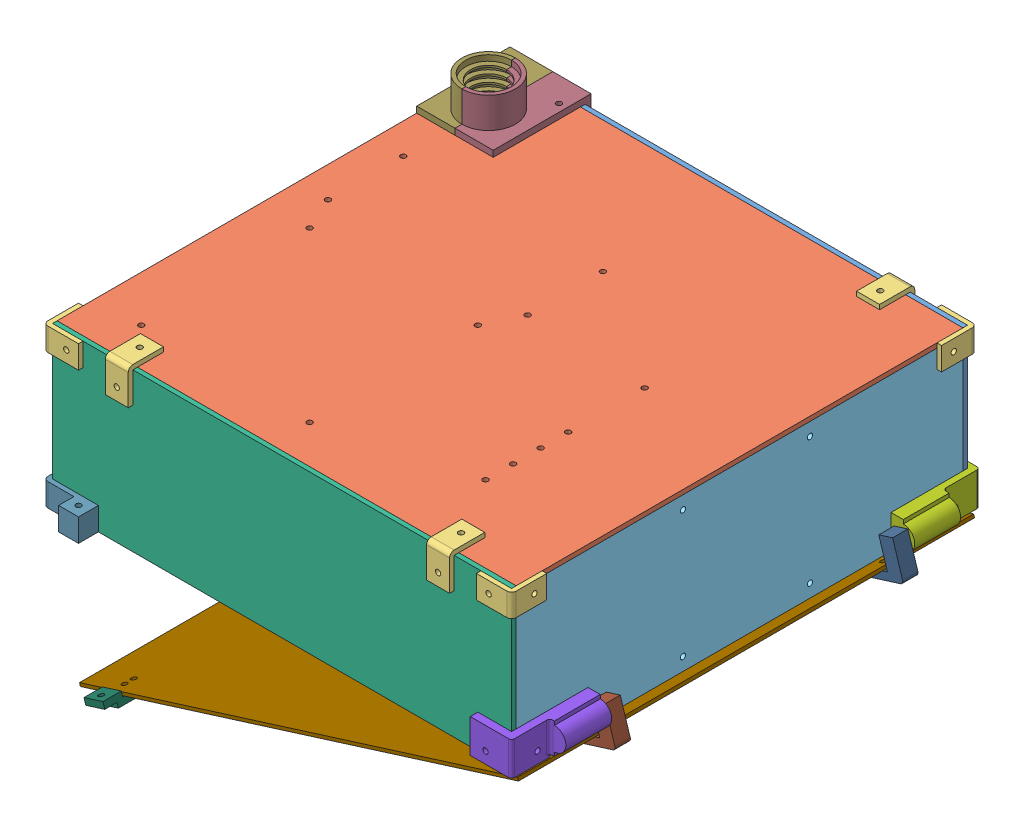
SolidWorks assembly last_assembly, configuration Default. Lengths in mm.
Overall size (321.18 220.37 315).
20 component instances, 15 part files, 55 mates.
Components (placement in the parent):
- baseup-1: baseup [Default] at (-19.8009 112.7119 215.9998) size (300 103 3)
- wall2-1: wall2 [Default] at (-19.8009 212.7119 218.9998) x (1 0 0) z (0 -1 0) size (300 292 3)
- holderr-1: holderr [Default] at (235.1991 204.2119 212.9998) x (0 -1 0) z (0 0 1) size (23 15 23)
- basen-1: basen [Default] at (-16.8009 109.7119 210.9998) x (0 0 1) z (-1 0 0) size (292 100 3)
- left_sidee-1: left_sidee [Default] at (280.1991 109.7119 210.9998) x (0 0 1) z (-1 0 0) size (292 100 3)
- upper_d-1: upper_d [Default] at (-19.8009 112.7119 510.9998) size (300 103 3)
- holderr-3: holderr [Default] at (235.1991 215.7119 505.4998) x (0 0 -1) z (0 -1 0) size (23 15 23)
- holderr-4: holderr [Default] at (25.1991 215.7119 505.4998) x (0 0 -1) z (0 -1 0) size (23 15 23)
- holderr-5: holderr [Default] at (-22.8009 205.2119 505.4998) x (0 0 -1) z (1 0 0) size (23 15 23)
- holderr-6: holderr [Default] at (283.1991 205.2119 505.4998) x (0 0 -1) z (-1 0 0) size (23 15 23)
- holderr-8: holderr [Default] at (271.6991 205.2119 212.9998) x (-1 0 0) z (0 0 1) size (23 15 23)
- hinge1-1: hinge1 [Default] at (280.1991 109.7119 265.9998) x (0 0 -1) z (1 0 0) size (54 22 37.5)
- hinge2-1: hinge2 [Default] at (283.1991 109.7119 516.9998) x (0 1 0) z (-1 0 0) size (22 55 37.5)
- kapi-1: kapi [Default] at (-2.151 18.2479 513.9998) x (0 0 -1) z (0.29874 -0.954334 0) size (298 300 2)
- revoluttt1-1: revoluttt1 [Default] at (290.2842 127.6039 275.9998) x (-0.954334 -0.29874 0) z (0.29874 -0.954334 0) size (29.5 27 23.91)
- upper_revolute-1: upper_revolute [Default] at (283.1267 125.3633 453.9998) x (0.954334 0.29874 0) z (0.29874 -0.954334 0) size (29.5 27 23.91)
- control_cable_up-1: control_cable_up [Default] at (-27.8009 212.7119 220.9998) x (0 0 1) z (0 1 0) size (64 28 46)
- control_cable-2: control_cable [Default] at (38.1991 212.7119 286.9998) x (0 0 -1) z (0 1 0) size (64 25 44)
- totucu-1: totucu [Default] at (-22.8009 117.2119 505.4998) x (0 0 -1) z (1 0 0) size (33 15 33)
- kapi_totucu-1: kapi_totucu [Default] at (13.7739 24.2808 526.9998) x (0 0 -1) z (-0.954334 -0.29874 0) size (30 7 13)
Mates (geometry in assembly coordinates):
- Concentric1: concentric aligned: cylinder of wall2-1 through (235.1991 209.7119 227.9998) axis (0 1 0) radius 1.75; cylinder of holderr-1 through (235.1991 192.7119 227.9998) axis (0 1 0) radius 1.75
- Coincident9: coincident anti-aligned: plane of baseup-1 through (-19.8009 112.7119 218.9998) normal (0 0 1); plane of basen-1 through (-26.8009 209.7119 218.9998) normal (0 0 -1)
- Coincident10: coincident anti-aligned: plane of wall2-1 through (-19.8009 209.7119 218.9998) normal (0 -1 0); plane of basen-1 through (-19.8009 209.7119 210.9998) normal (0 1 0)
- Coincident11: coincident anti-aligned: plane of wall2-1 through (-19.8009 209.7119 218.9998) normal (0 -1 0); plane of basen-1 through (-19.8009 209.7119 210.9998) normal (0 1 0)
- Coincident12: coincident aligned: plane of wall2-1 through (-19.8009 209.7119 218.9998) normal (-1 0 0); plane of basen-1 through (-19.8009 109.7119 210.9998) normal (-1 0 0)
- Coincident13: coincident aligned: plane of baseup-1 through (-19.8009 212.7119 218.9998) normal (0 1 0); plane of wall2-1 through (-19.8009 212.7119 218.9998) normal (0 1 0)
- Coincident14: coincident anti-aligned: plane of wall2-1 through (-19.8009 209.7119 218.9998) normal (0 -1 0); plane of left_sidee-1 through (277.1991 209.7119 210.9998) normal (0 1 0)
- Coincident15: coincident anti-aligned: plane of baseup-1 through (-19.8009 112.7119 218.9998) normal (0 0 1); plane of left_sidee-1 through (270.1991 209.7119 218.9998) normal (0 0 -1)
- Coincident16: coincident aligned: plane of wall2-1 through (280.1991 209.7119 218.9998) normal (1 0 0); plane of left_sidee-1 through (280.1991 109.7119 210.9998) normal (1 0 0)
- Coincident23: coincident aligned: plane of basen-1 through (-19.8009 109.7119 210.9998) normal (-1 0 0); plane of upper_d-1 through (-19.8009 212.7119 510.9998) normal (-1 0 0)
- Coincident24: coincident aligned: plane of wall2-1 through (-19.8009 212.7119 218.9998) normal (0 1 0); plane of upper_d-1 through (280.1991 212.7119 510.9998) normal (0 1 0)
- Coincident25: coincident anti-aligned: plane of basen-1 through (-19.8009 109.7119 510.9998) normal (0 0 1); plane of upper_d-1 through (-19.8009 112.7119 510.9998) normal (0 0 -1)
- Concentric7: concentric aligned: cylinder of upper_d-1 through (235.1991 200.7119 510.9998) axis (0 0 1) radius 1.75; cylinder of holderr-3 through (235.1991 200.7119 493.9998) axis (0 0 1) radius 1.75
- Concentric8: concentric aligned: cylinder of wall2-1 through (235.1991 209.7119 501.9998) axis (0 1 0) radius 1.75; cylinder of holderr-3 through (235.1991 192.7119 501.9998) axis (0 1 0) radius 1.75
- Concentric9: concentric aligned: cylinder of wall2-1 through (25.1991 209.7119 501.9998) axis (0 1 0) radius 1.75; cylinder of holderr-4 through (25.1991 192.7119 501.9998) axis (0 1 0) radius 1.75
- Concentric10: concentric aligned: cylinder of upper_d-1 through (25.1991 200.7119 510.9998) axis (0 0 1) radius 1.75; cylinder of holderr-4 through (25.1991 200.7119 493.9998) axis (0 0 1) radius 1.75
- Concentric11: concentric aligned: cylinder of upper_d-1 through (-7.8009 205.2119 510.9998) axis (0 0 1) radius 1.75; cylinder of holderr-5 through (-7.8009 205.2119 493.9998) axis (0 0 1) radius 1.75
- Coincident26: coincident anti-aligned: circle of basen-1; cylinder of holderr-5 through (0.1991 205.2119 501.9998) axis (-1 0 0) radius 1.75
- Concentric12: concentric aligned: cylinder of upper_d-1 through (268.1991 205.2119 510.9998) axis (0 0 1) radius 1.75; cylinder of holderr-6 through (268.1991 205.2119 493.9998) axis (0 0 1) radius 1.75
- Concentric13: concentric aligned: cylinder of left_sidee-1 through (277.1991 205.2119 501.9998) axis (1 0 0) radius 1.75; cylinder of holderr-6 through (260.1991 205.2119 501.9998) axis (1 0 0) radius 1.75
- Coincident34: coincident anti-aligned: plane of wall2-1 through (-19.8009 212.7119 218.9998) normal (0 1 0); plane of holderr-1 through (242.6991 212.7119 235.9998) normal (0 -1 0)
- Coincident35: coincident aligned: circle of baseup-1; cylinder of holderr-8 through (268.1991 205.2119 235.9998) axis (0 0 -1) radius 1.75
- Coincident36: coincident anti-aligned: plane of baseup-1 through (-19.8009 112.7119 215.9998) normal (0 0 -1); plane of holderr-8 through (271.6991 205.2119 215.9998) normal (0 0 1)
- Coincident37: coincident anti-aligned: plane of left_sidee-1 through (280.1991 109.7119 210.9998) normal (1 0 0); plane of holderr-8 through (280.1991 197.7119 235.9998) normal (-1 0 0)
- Coincident40: coincident anti-aligned: plane of baseup-1 through (-19.8009 112.7119 215.9998) normal (0 0 -1); plane of holderr-1 through (235.1991 204.2119 215.9998) normal (0 0 1)
- Coincident45: coincident aligned: plane of left_sidee-1 through (277.1991 109.7119 210.9998) normal (0 -1 0); plane of hinge1-1 through (283.1991 109.7119 265.9998) normal (0 -1 0)
- Coincident46: coincident anti-aligned: plane of left_sidee-1 through (280.1991 109.7119 210.9998) normal (1 0 0); plane of hinge1-1 through (280.1991 109.7119 265.9998) normal (-1 0 0)
- Concentric17: concentric aligned: cylinder of baseup-1 through (268.1991 117.2119 218.9998) axis (0 0 -1) radius 1.75; cylinder of hinge1-1 through (268.1991 117.2119 265.9998) axis (0 0 -1) radius 1.75
- Concentric18: concentric aligned: cylinder of baseup-1 through (268.1991 117.2119 218.9998) axis (0 0 -1) radius 1.75; cylinder of hinge1-1 through (268.1991 117.2119 265.9998) axis (0 0 -1) radius 1.75
- Coincident47: coincident anti-aligned: plane of baseup-1 through (-19.8009 112.7119 215.9998) normal (0 0 -1); plane of hinge1-1 through (258.1991 109.7119 215.9998) normal (0 0 1)
- Coincident49: coincident anti-aligned: plane of left_sidee-1 through (280.1991 109.7119 210.9998) normal (1 0 0); plane of hinge2-1 through (280.1991 109.7119 516.9998) normal (-1 0 0)
- Coincident51: coincident aligned: plane of left_sidee-1 through (277.1991 109.7119 210.9998) normal (0 -1 0); plane of hinge2-1 through (280.1991 109.7119 516.9998) normal (0 -1 0)
- Concentric21: concentric aligned: cylinder of upper_d-1 through (268.1991 117.2119 510.9998) axis (0 0 1) radius 1.75; cylinder of hinge2-1 through (268.1991 117.2119 494.9998) axis (0 0 1) radius 1.75
- Coincident52: coincident anti-aligned: plane of upper_d-1 through (-19.8009 112.7119 513.9998) normal (0 0 1); plane of hinge2-1 through (258.1991 131.7119 513.9998) normal (0 0 -1)
- Coincident54: coincident aligned: plane of baseup-1 through (-19.8009 112.7119 215.9998) normal (0 0 -1); plane of kapi-1 through (-1.5535 16.3393 215.9998) normal (0 0 -1)
- Concentric23: concentric aligned: cylinder of hinge1-1 through (288.1991 121.7119 245.9998) axis (0 0 1) radius 4; cylinder of revoluttt1-1 through (288.1991 121.7119 248.9998) axis (0 0 1) radius 3.75
- Coincident63: coincident anti-aligned: plane of hinge1-1 through (283.1991 109.7119 265.9998) normal (0 0 1); plane of revoluttt1-1 through (293.2716 118.0605 265.9998) normal (0 0 -1)
- Concentric24: concentric aligned: cylinder of kapi-1 through (274.7161 123.7784 270.9998) axis (0.29874 -0.954334 0) radius 1.75; cylinder of revoluttt1-1 through (275.0148 122.824 270.9998) axis (0.29874 -0.954334 0) radius 1.75
- Concentric25: concentric aligned: cylinder of kapi-1 through (266.6042 121.2391 270.9998) axis (0.29874 -0.954334 0) radius 1.75; cylinder of revoluttt1-1 through (266.903 120.2847 270.9998) axis (0.29874 -0.954334 0) radius 1.75
- Concentric27: concentric aligned: cylinder of hinge2-1 through (288.1991 121.7119 483.9998) axis (0 0 -1) radius 4; cylinder of upper_revolute-1 through (288.1991 121.7119 480.9998) axis (0 0 -1) radius 3.75
- Coincident67: coincident anti-aligned: plane of hinge2-1 through (280.1991 109.7119 463.9998) normal (0 0 -1); plane of upper_revolute-1 through (286.1141 115.82 463.9998) normal (0 0 1)
- Concentric29: concentric aligned: cylinder of kapi-1 through (271.9816 104.0611 458.9998) axis (0.29874 -0.954334 0) radius 1.75; cylinder of upper_revolute-1 through (267.7723 117.5076 458.9998) axis (0.29874 -0.954334 0) radius 1.75
- Concentric30: concentric aligned: cylinder of wall2-1 through (5.1991 219.7119 253.9998) axis (0 -1 0) radius 16; cylinder of control_cable_up-1 through (5.1991 236.7119 253.9998) axis (0 -1 0) radius 17.5
- Concentric31: concentric anti-aligned: cylinder of basen-1 through (-19.8009 205.2119 227.9998) axis (1 0 0) radius 1.75; cylinder of control_cable_up-1 through (5.1991 205.2119 227.9998) axis (-1 0 0) radius 1.75
- Concentric32: concentric anti-aligned: cylinder of control_cable_up-1 through (5.1991 236.7119 253.9998) axis (0 -1 0) radius 17.5; cylinder of control_cable-2 through (5.1991 212.7119 253.9998) axis (0 1 0) radius 15
- Coincident72: coincident anti-aligned: plane of baseup-1 through (-19.8009 112.7119 215.9998) normal (0 0 -1); plane of control_cable-2 through (5.1991 192.7119 215.9998) normal (0 0 1)
- Concentric33: concentric aligned: cylinder of baseup-1 through (25.1991 200.7119 218.9998) axis (0 0 -1) radius 1.75; cylinder of control_cable-2 through (25.1991 200.7119 231.9998) axis (0 0 -1) radius 1.75
- Concentric34: concentric anti-aligned: cylinder of basen-1 through (-19.8009 117.2119 501.9998) axis (1 0 0) radius 1.75; cylinder of totucu-1 through (0.1991 117.2119 501.9998) axis (-1 0 0) radius 1.75
- Concentric35: concentric aligned: cylinder of upper_d-1 through (-7.8009 117.2119 510.9998) axis (0 0 1) radius 1.75; cylinder of totucu-1 through (-7.8009 117.2119 493.9998) axis (0 0 1) radius 1.75
- Concentric36: concentric aligned: cylinder of kapi-1 through (20.2758 25.2683 506.9998) axis (0.29874 -0.954334 0) radius 1.75; cylinder of kapi_totucu-1 through (19.9771 26.2227 506.9998) axis (0.29874 -0.954334 0) radius 1.75
- Concentric37: concentric aligned: cylinder of kapi-1 through (20.2758 25.2683 500.9998) axis (0.29874 -0.954334 0) radius 1.75; cylinder of kapi_totucu-1 through (19.9771 26.2227 500.9998) axis (0.29874 -0.954334 0) radius 1.75
- Concentric38: concentric aligned: cylinder of kapi-1 through (280.0934 106.6004 458.9998) axis (0.29874 -0.954334 0) radius 1.75; cylinder of upper_revolute-1 through (275.8842 120.0469 458.9998) axis (0.29874 -0.954334 0) radius 1.75
- Concentric39: concentric aligned: cylinder of kapi-1 through (271.9816 104.0611 458.9998) axis (0.29874 -0.954334 0) radius 1.75; cylinder of upper_revolute-1 through (267.7723 117.5076 458.9998) axis (0.29874 -0.954334 0) radius 1.75
- Coincident77: coincident anti-aligned: plane of kapi-1 through (-1.5535 16.3393 513.9998) normal (0.29874 -0.954334 0); plane of upper_revolute-1 through (268.7617 100.9574 453.9998) normal (-0.29874 0.954334 0)
- Coincident78: coincident anti-aligned: plane of kapi-1 through (-1.5535 16.3393 513.9998) normal (0.29874 -0.954334 0); plane of kapi_totucu-1 through (27.0765 25.3015 496.9998) normal (-0.29874 0.954334 0)
